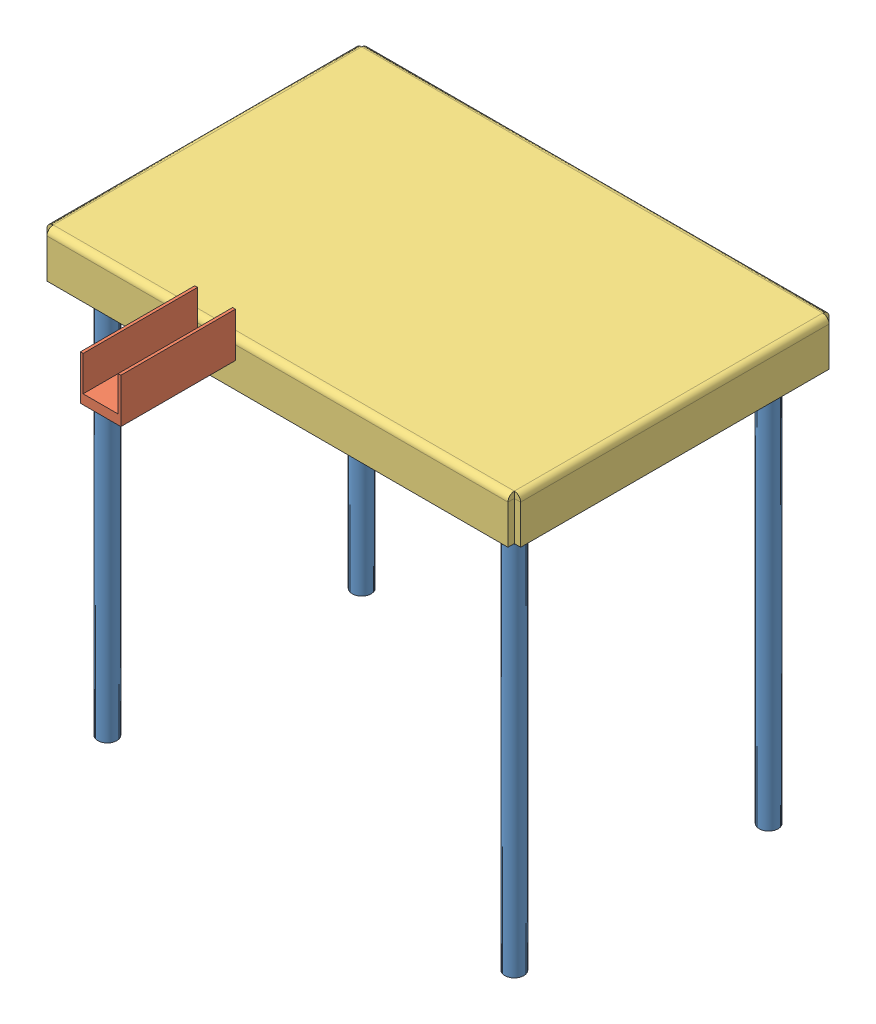
SolidWorks assembly Assem1, configuration Default. Lengths in mm.
Overall size (946.15 1003.3 890.97).
3 component instances, 3 part files, 7 mates.
Components (placement in the parent):
- M37 Metal Table-1: M37 Metal Table [Default] at (-122.75 340.8931 1031.9817) size (914.4 863.6 609.6)
- Goose Output-1: Goose Output [Default] at (190.4608 417.0931 1068.8723) size (80.96 88.9 228.6)
- Table Topper-1: Table Topper [Default] at (-125.925 345.3431 1035.1567) size (946.15 90.8 641.35)
Mates (geometry in assembly coordinates):
- Width1: width aligned: plane of M37 Metal Table-1 through (791.65 366.2931 1031.9817) normal (1 0 0); plane of Table Topper-1 through (-122.75 366.2931 1031.9817) normal (-1 0 0); plane of M37 Metal Table-1 through (807.525 423.4431 1035.1567) normal (1 0 0); plane of Table Topper-1 through (-138.625 423.4431 1035.1567) normal (-1 0 0)
- Width2: width aligned: plane of M37 Metal Table-1 through (-122.75 366.2931 1031.9817) normal (0 0 1); plane of Table Topper-1 through (-122.75 366.2931 422.3817) normal (0 0 -1); plane of M37 Metal Table-1 through (-125.925 423.4431 1047.8567) normal (0 0 1); plane of Table Topper-1 through (-125.925 423.4431 406.5067) normal (0 0 -1)
- Distance1: distance = 863.6 mm aligned: plane of M37 Metal Table-1 through (-122.75 -446.5069 1031.9817) normal (0 -1 0); plane of Goose Output-1 through (271.4233 417.0931 1297.4723) normal (0 -1 0)
- LimitDistance1: limit distance = 536.1018 mm aligned: plane of Goose Output-1 through (271.4233 505.9931 1297.4723) normal (1 0 0); plane of Table Topper-1 through (807.525 423.4431 1035.1567) normal (1 0 0)
- LimitDistance2: limit distance = 329.0857 mm aligned: plane of Table Topper-1 through (-138.625 423.4431 1035.1567) normal (-1 0 0); plane of Goose Output-1 through (190.4608 417.0931 1297.4723) normal (-1 0 0)
- Parallel1: parallel aligned: plane of Goose Output-1 through (196.017 436.1431 1297.4723) normal (0 1 0); plane of Table Topper-1 through (-125.925 436.1431 1035.1567) normal (0 1 0)
- Coincident5: coincident aligned: plane of Goose Output-1 through (196.017 436.1431 1297.4723) normal (0 1 0); plane of Table Topper-1 through (-125.925 436.1431 1035.1567) normal (0 1 0)
